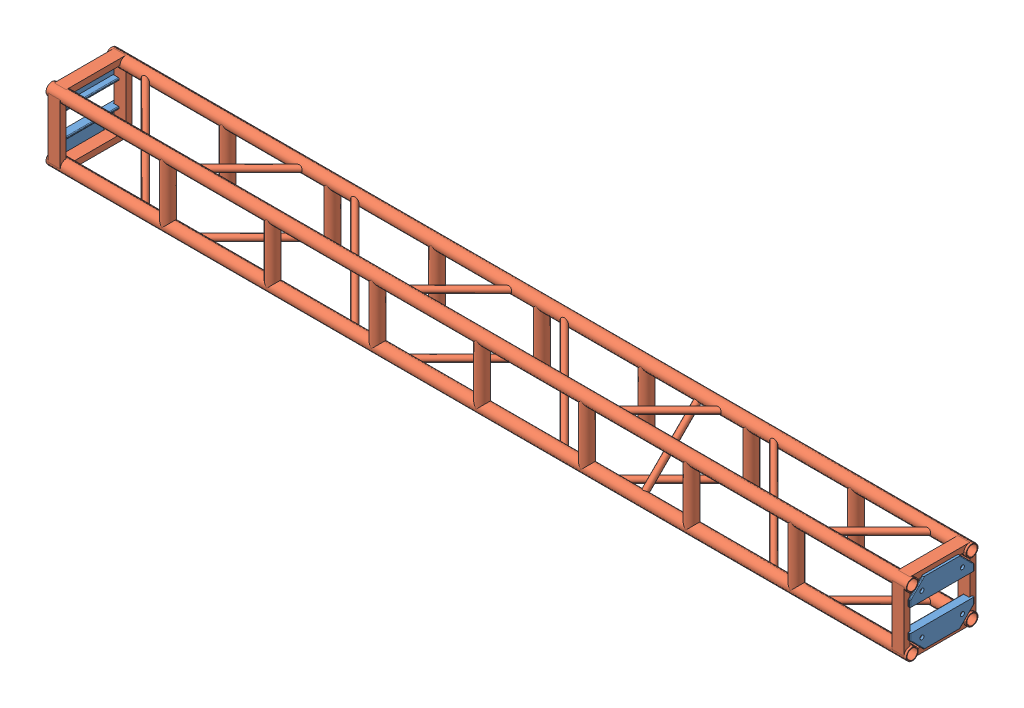
SolidWorks assembly GE-20005, configuration Default. Lengths in mm.
Overall size (3657.6 304.8 304.8).
5 component instances, 2 part files, 0 mates.
Components (placement in the parent):
- Connection Plate _ TS Standard-8: Connection Plate _ TS Standard [Default] at (-1811.3375 -90.7415 0) x (0 0 -1) z (1 0 0) size (273.05 85.72 34.92)
- Connection Plate _ TS Standard-9: Connection Plate _ TS Standard [Default] at (-1811.3375 90.7415 0) x (0 0 1) z (1 0 0) size (273.05 85.72 34.92)
- Connection Plate _ TS Standard-10: Connection Plate _ TS Standard [Default] at (1811.3375 -90.7415 0) x (0 0 1) z (-1 0 0) size (273.05 85.72 34.92)
- Connection Plate _ TS Standard-7: Connection Plate _ TS Standard [Default] at (1811.3375 90.7415 0) x (0 0 -1) z (-1 0 0) size (273.05 85.72 34.92)
- GE-20005 - 01-1: GE-20005 - 01 [Default] at origin size (3657.6 304.8 304.8)
